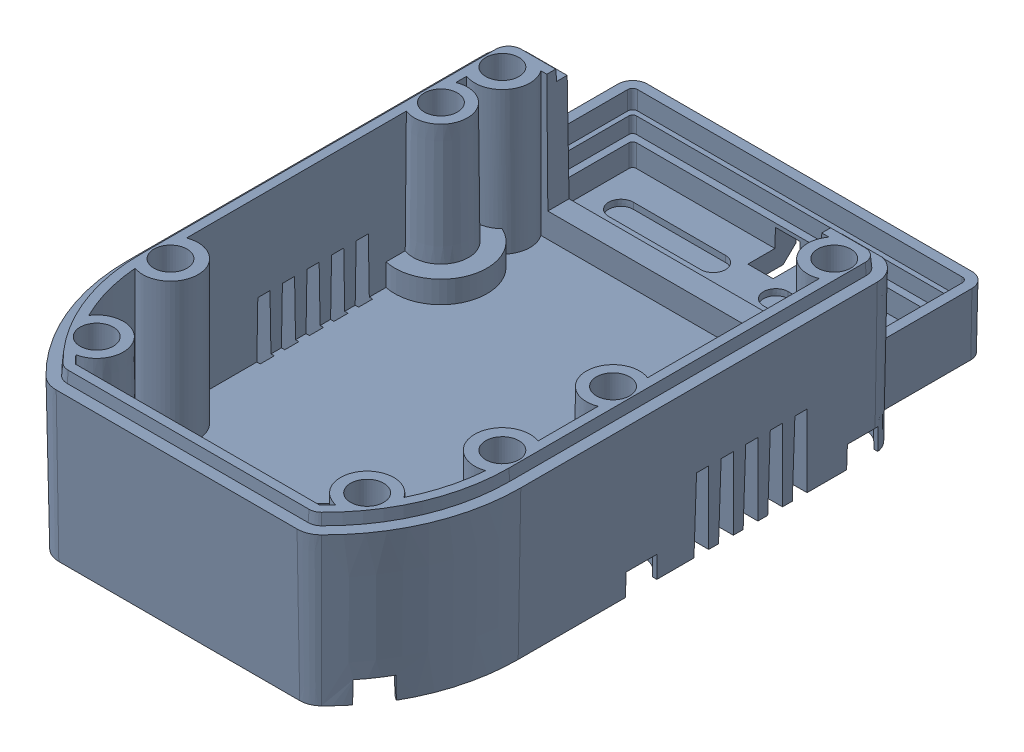
SolidWorks assembly 60K-ボトムケースASSY, configuration ﾃﾞﾌｫﾙﾄ. Lengths in mm.
Overall size (32 18.6 51.5).
2 component instances, 2 part files, 0 mates.
Components (placement in the parent):
- 60K-ボトムケース-1: 60K-ボトムケース [ﾃﾞﾌｫﾙﾄ] at (0 5.7 0) size (32 18.6 51.5)
- 60K-インサートナット_L=7mm-1: 60K-インサートナット_L=7mm [ﾃﾞﾌｫﾙﾄ] at (0 -5 0) x (-0.600327 0 -0.799755) z (-0.799755 0 0.600327) size (4.5 7 4.5)
